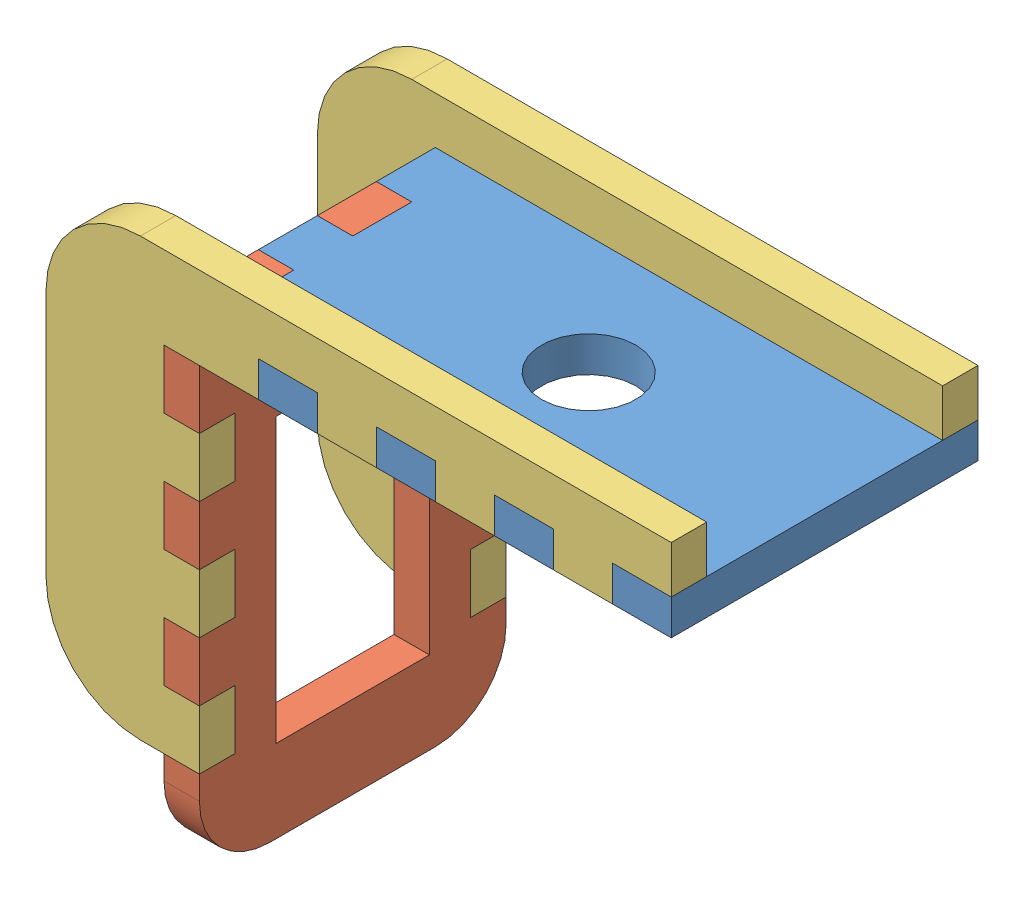
SolidWorks assembly roll-pan linkage plate, configuration Default. Lengths in mm.
Overall size (53 45 26).
4 component instances, 3 part files, 6 mates.
Components (placement in the parent):
- roll-pan base plate-4: roll-pan base plate [Default] at (-16.4079 3.9529 39.0307) size (43 3 26)
- roll-pan servo holder plate-6: roll-pan servo holder plate [Default] at (-37.9079 -16.5471 39.0307) x (0 -1 0) z (0 0 1) size (41 3 26)
- roll-pan joiner plate-1: roll-pan joiner plate [Default] at (-25.4079 -9.0471 52.0307) x (1 0 0) z (0 1 0) size (53 3 37)
- roll-pan joiner plate-2: roll-pan joiner plate [Default] at (-25.4079 -9.0471 29.0307) x (1 0 0) z (0 1 0) size (53 3 37)
Mates (geometry in assembly coordinates):
- Coincident1: coincident anti-aligned: plane of roll-pan base plate-4 through (-36.4079 5.4529 26.0307) normal (-1 0 0); plane of roll-pan servo holder plate-6 through (-36.4079 -16.5471 39.0307) normal (1 0 0)
- Coincident2: coincident anti-aligned: plane of roll-pan base plate-4 through (-39.4079 3.9529 34.0307) normal (0 0 1); plane of roll-pan servo holder plate-6 through (-37.9079 5.4529 34.0307) normal (0 0 -1)
- Coincident3: coincident anti-aligned: plane of roll-pan base plate-4 through (-16.4079 2.4529 39.0307) normal (0 -1 0); plane of roll-pan servo holder plate-6 through (-36.4079 2.4529 26.0307) normal (0 1 0)
- Coincident5: coincident: plane of roll-pan servo holder plate-6 through (-39.4079 -16.5471 39.0307) normal (-1 0 0); plane of roll-pan joiner plate-1 through (-38.2465 -8.9045 37.1257) normal (1 0 0)
- Coincident6: coincident: plane of roll-pan servo holder plate-6 through (-30.5769 -16.5471 49.0307) normal (0 0 1); plane of roll-pan joiner plate-1 through (-24.2465 -8.9045 34.1257) normal (0 0 -1)
- Coincident7: coincident anti-aligned: plane of roll-pan base plate-4 through (-16.4079 5.4529 39.0307) normal (0 1 0); plane of roll-pan joiner plate-1 through (-25.4079 5.4529 52.0307) normal (0 -1 0)
